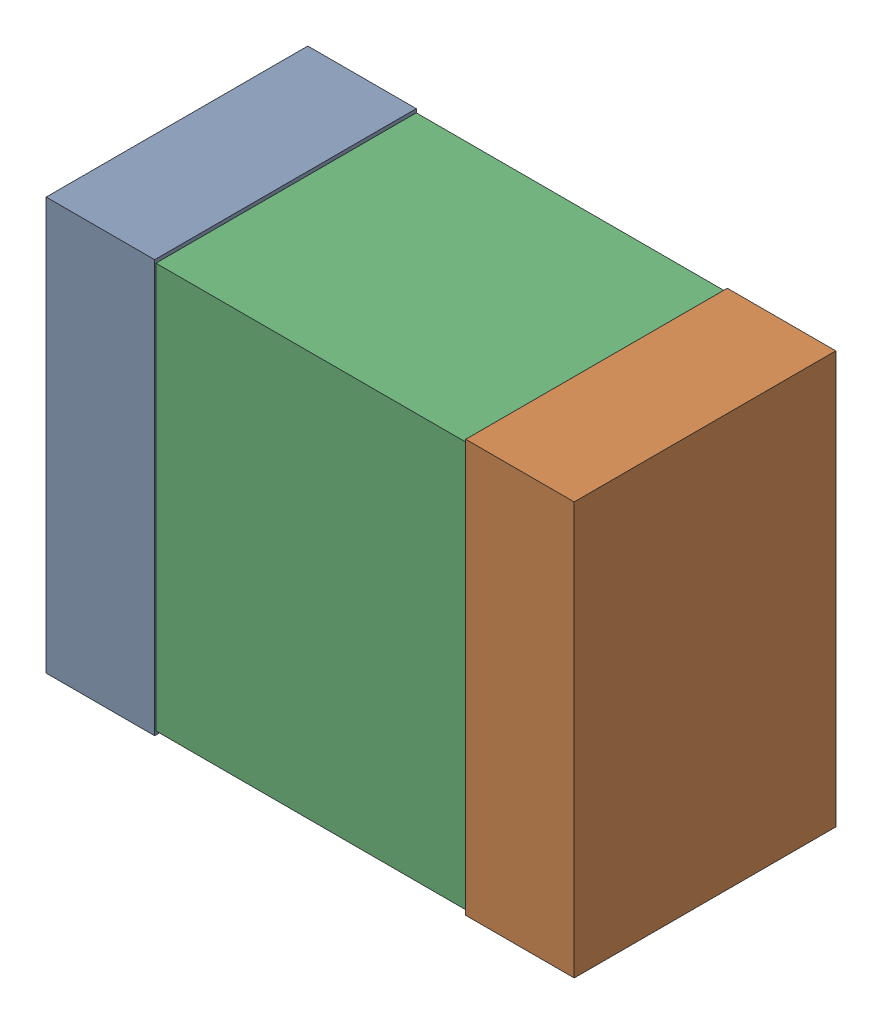
SolidWorks assembly CinB1_1Kanaloa_v2.0.0_Power, configuration Default. Lengths in mm.
Overall size (3.65 2.85 1.81).
6 component instances, 2 part files, 0 mates.
Components (placement in the parent):
- 334788400-1: 334788400 [Default] at (126.8 46.575 0) size (0.75 2.85 1.81)
  - Extruded_5-1: Extruded_5 [Default] at origin size (0.75 2.85 1.81)
- 334788400-2: 334788400 [Default] at (129.7 46.575 0) size (0.75 2.85 1.81)
  - Extruded_5-1: Extruded_5 [Default] at origin size (0.75 2.85 1.81)
- 334788784-1: 334788784 [Default] at (128.25 46.575 0) size (3.6 2.8 1.8)
  - Extruded_6-1: Extruded_6 [Default] at origin size (3.6 2.8 1.8)
